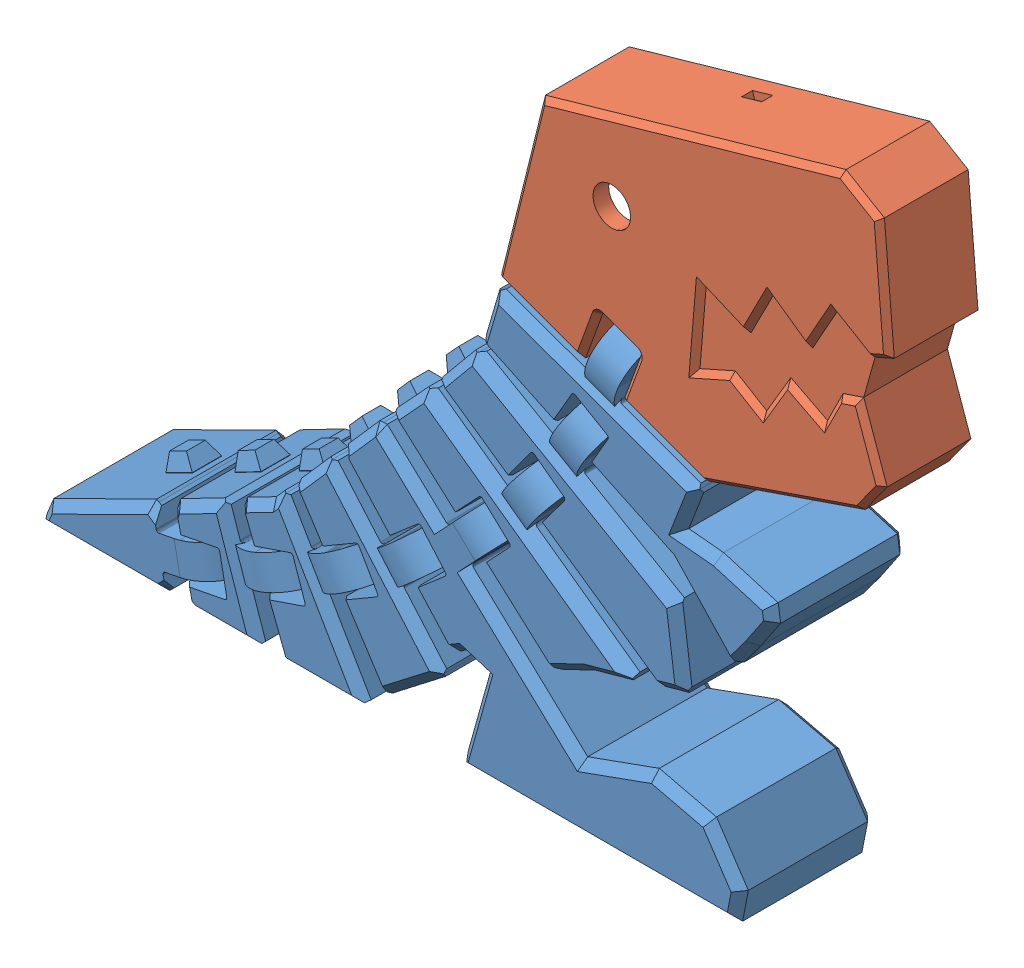
SolidWorks assembly MK2.1.0 Head+Body, configuration Default. Lengths in mm.
Overall size (113.8 94.45 18.21).
2 component instances, 2 part files, 2 mates.
Components (placement in the parent):
- MK2.1.0 Body-1: MK2.1.0 Body [Default] at (-107.0351 17.4452 -7.7839) x (1 0.000012 0) z (0 0 1) size (98.19 60.49 18.21)
- MK2.1.0 Head Bottom-1: MK2.1.0 Head Bottom [Default] at (-107.0497 17.4514 -7.7839) size (52.54 45.27 11.91)
Mates (geometry in assembly coordinates):
- Concentric1: concentric anti-aligned: cylinder of 1.4 Flexi Rex No Head by Lee + Connor-1 through (13.7977 -25.829 1.3161) axis (-0.93963 0.342192 0) radius 2.8; cylinder of MK2.0 Flex-E Rex Head Bottom-1 through (-38.9482 -6.6201 1.3161) axis (0.93963 -0.342192 0) radius 2.1
- Coincident1: coincident aligned: plane of 1.4 Flexi Rex No Head by Lee + Connor-1 through (-107.0351 17.4452 10.4161) normal (0 0 1); plane of MK2.0 Flex-E Rex Head Bottom-1 through (-107.0497 17.4514 10.4161) normal (0 0 1)
